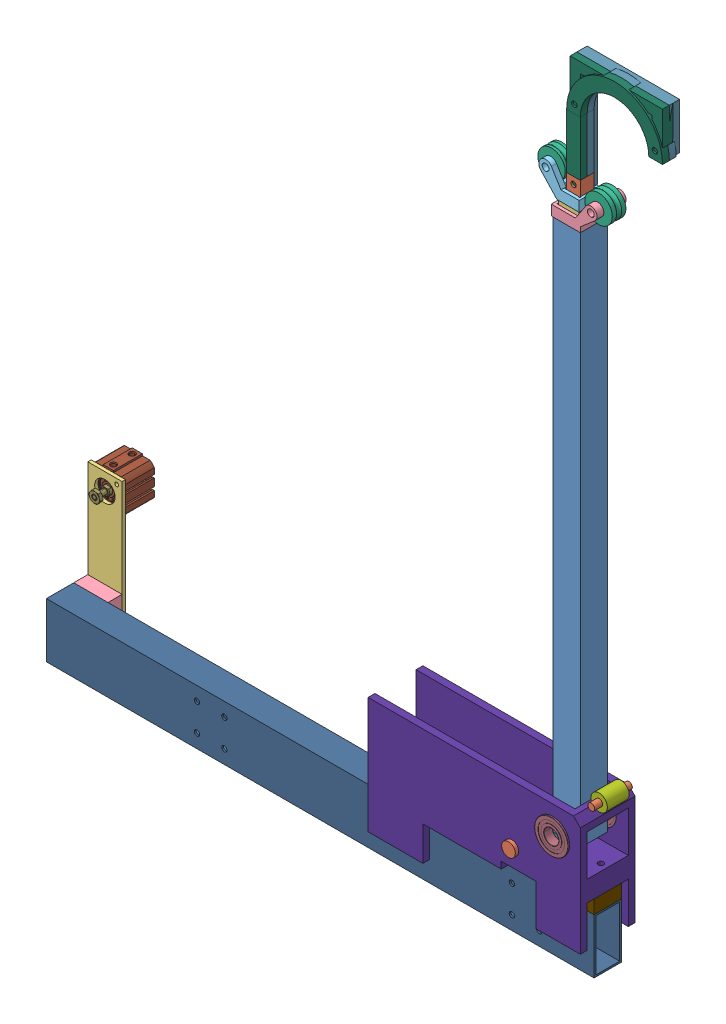
SolidWorks assembly Climber Assembly, configuration Default. Lengths in mm.
Overall size (565.24 723.26 84.45).
30 component instances, 22 part files, 39 mates.
Components (placement in the parent):
- Climber-1: Climber [Default] at (16.6995 73.025 101.2015) x (-1 0 0) z (0 0 -1) size (78.21 544.54 26.99) (flexible)
  - Tubes-1: Tubes [Default] at origin size (25.4 501.65 25.4)
  - Tubes3-1: Tubes3 [Default] at (0 21.59 0) size (12.7 508 12.7)
  - Tubes2-1: Tubes2 [Default] at (1.0954 19.05 0) size (19.05 495.3 19.05)
  - Cap-1: Cap [Default] at (0 504.19 0) x (-1 0 0) z (0 0 1) size (42.42 26.35 26.99)
  - Cap2-1: Cap2 [Default] at (1.0954 516.89 0) x (-1 0 0) z (0 0 1) size (37.5 26.99 20.64)
  - Roller-1: Roller [Default] at (21.9234 528.0025 -4.7942) x (0.375568 0.926795 0) z (0 0 1) size (25.4 25.4 9.59)
  - Roller-2: Roller [2nd Stage] at (-23.2093 515.3025 -6.3182) x (0.375568 0.926795 0) z (0 0 1) size (25.4 25.4 12.64)
  - Space-1: Space [Default] at (-27.5695 42.3738 -10.16) x (0.938392 0.345574 0) z (0 0 1) size (15.24 15.24 20.32)
  - Part1-1: Part1 [Default] at (2.2782 31.75 -0.9829) x (1 0 0) z (0 1 0) size (22.12 22.12 25.4)
  - Part2-1: Part2 [Default] at (0 34.29 0) x (0 0 1) z (0 1 0) size (15.96 15.78 25.4)
- Robot mount-1: Robot mount [Default] at (-465.9005 0 101.2015) x (0 0 -1) z (1 0 0) size (25.4 50.8 508)
- Pneumatic_Cylinder-1: Pneumatic_Cylinder [Default] at (-450.1144 100.2284 58.7835) size (31.75 33.34 39.89) (flexible)
  - Pneumatic_Cylinder_body-1: Pneumatic_Cylinder_body [Default] at origin size (31.75 33.34 26.92)
  - Pneumatic_Cylinder_pistion-1: Pneumatic_Cylinder_pistion [Default] x (0.356813 -0.934176 0) z (0 0 1) size (18.95 18.95 35.28)
- 0.5 in Bearing-1: 0.5 in Bearing [Default] at (16.6995 82.55 124.2202) x (0.99994 -0.010999 0) z (0 0 1) size (31.12 31.12 7.94)
- Hook 2-1: Hook 2 [Default] at (-15.7466 559.6581 -9.8676) size (88.9 107.95 12.7)
  - Hook Left-1: Hook Left [Default] at (32.4461 30.2569 104.7191) size (88.9 107.95 11.11)
  - Hook Right-1: Hook Right [Default] at (32.4461 30.2569 111.0691) size (88.9 107.95 11.11)
- Pin-1: Pin [Default] at (16.6995 136.525 85.9615) x (-0.380163 -0.92492 0) z (0 0 1) size (10.79 10.79 19.05)
- Hinge Mount-1: Hinge Mount [Default] at (16.6995 47.625 101.2015) x (0 0 1) z (-1 0 0) size (50.8 107.95 196.85)
- Foam-1: Foam [Default] at (-29.338 31.75 113.9015) size (71.44 12.7 25.4)
- 0.5 in Bearing-4: 0.5 in Bearing [Default] at (16.6995 82.55 78.1827) x (-0.923728 -0.383049 0) z (0 0 -1) size (31.12 31.12 7.94)
- Spring-body-1: Spring-body [Default] at (-21.4005 53.975 98.0265) x (-0.715331 -0.698786 0) z (0 0 1) size (26.37 26.37 19.05)
- Rod-1: Rod [Default] at (16.6995 82.55 72.6265) x (-0.463083 0.886315 0) z (0 0 1) size (12.7 12.7 57.15) (hidden)
- Rod-2: Rod [Default] at (-21.4005 53.975 72.6265) x (-0.920175 0.391507 0) z (0 0 1) size (12.7 12.7 57.15)
- Rod-3: Rod [Small] at (44.2691 115.3988 83.739) x (-0.997762 0.066863 0) z (0 0 1) size (6.35 6.35 34.92)
- Foam-2: Foam [Short] at (-103.9505 31.75 88.5015) x (-1 0 0) z (0 0 -1) size (50.8 12.7 25.4)
- mount for the piston mount thingie-1: mount for the piston mount thingie [Default] at (-465.9005 -31.3055 72.2455) size (31.75 141.41 3.17)
- spacer for the piston mount thingie-1: spacer for the piston mount thingie [Default] at (-465.9005 -25.4 75.4205) size (31.75 50.8 13.08)
Mates (geometry in assembly coordinates):
- Coincident39: coincident anti-aligned: plane of Climber-1/Tubes3-1 through (16.6995 602.615 101.2015) normal (0 1 0); plane of Hook 2-1/Hook Left-1 through (16.6995 602.615 94.8515) normal (0 -1 0)
- Concentric9: concentric aligned: cylinder of Pin-1 through (16.6995 136.525 105.0115) axis (0 0 -1) radius 3.937; cylinder of Climber-1/Tubes-1 through (16.6995 136.525 104.4574) axis (0 0 -1) radius 5.08
- LimitDistance1: limit distance = 0 mm anti-aligned: plane of Climber-1/Tubes-1 through (29.3995 574.675 88.5015) normal (0 0 -1); plane of Pin-1 through (16.6995 136.525 88.5015) normal (0 0 1)
- Parallel1: parallel anti-aligned: plane of Robot mount-1 through (42.0995 -25.4 88.5015) normal (0 0 -1); plane of Hinge Mount-1 through (-8.7005 0 82.1515) normal (0 0 1)
- Width2: width anti-aligned: plane of Hinge Mount-1 through (-8.7005 0 82.1515) normal (0 0 1); plane of Robot mount-1 through (-8.7005 38.1 120.2515) normal (0 0 -1); plane of Hinge Mount-1 through (42.0995 -25.4 88.5015) normal (0 0 -1); plane of Robot mount-1 through (42.0995 -25.4 113.9015) normal (0 0 1)
- Coincident41: coincident anti-aligned: plane of Robot mount-1 through (42.0995 25.4 113.9015) normal (0 1 0); plane of Foam-1 through (-29.338 25.4 113.9015) normal (0 -1 0)
- Coincident42: coincident aligned: plane of Robot mount-1 through (42.0995 -25.4 88.5015) normal (0 0 -1); plane of Foam-1 through (-29.338 38.1 88.5015) normal (0 0 -1)
- Coincident43: coincident anti-aligned: plane of Hinge Mount-1 through (-8.7005 38.1 82.1515) normal (0 -1 0); plane of Foam-1 through (-29.338 38.1 113.9015) normal (0 1 0)
- Coincident44: coincident aligned: plane of Hinge Mount-1 through (42.0995 47.625 101.2015) normal (1 0 0); plane of Foam-1 through (42.0995 38.1 113.9015) normal (1 0 0)
- Coincident45: coincident aligned: plane of Robot mount-1 through (42.0995 0 101.2015) normal (1 0 0); plane of Foam-1 through (42.0995 38.1 113.9015) normal (1 0 0)
- Concentric10: concentric aligned: cylinder of Hinge Mount-1 through (16.6995 82.55 126.6015) axis (0 0 -1) radius 14.2875; cylinder of 0.5 in Bearing-4 through (16.6995 82.55 24.9338) axis (0 0 -1) radius 14.2875
- Coincident46: coincident anti-aligned: plane of Hinge Mount-1 through (-8.7005 107.95 75.8015) normal (0 0 -1); plane of 0.5 in Bearing-4 through (11.2267 95.7478 75.8015) normal (0 0 1)
- Concentric11: concentric anti-aligned: cylinder of 0.5 in Bearing-1 through (16.6995 82.55 177.4691) axis (0 0 1) radius 14.2875; cylinder of Hinge Mount-1 through (16.6995 82.55 126.6015) axis (0 0 -1) radius 14.2875
- Coincident47: coincident anti-aligned: plane of 0.5 in Bearing-1 through (16.8567 96.8366 126.6015) normal (0 0 -1); plane of Hinge Mount-1 through (-8.7005 0 126.6015) normal (0 0 1)
- Concentric12: concentric aligned: cylinder of Climber-1/Tubes-1 through (16.6995 82.55 113.9015) axis (0 0 -1) radius 6.35; cylinder of 0.5 in Bearing-4 through (16.6995 82.55 24.9338) axis (0 0 -1) radius 6.875
- Width3: width anti-aligned: plane of Climber-1/Tubes-1 through (29.3995 574.675 113.9015) normal (0 0 1); plane of Hinge Mount-1 through (29.3995 574.675 88.5015) normal (0 0 -1); plane of Climber-1/Tubes-1 through (-8.7005 107.95 120.2515) normal (0 0 -1); plane of Hinge Mount-1 through (-8.7005 57.15 82.1515) normal (0 0 1)
- Coincident52: coincident anti-aligned: plane of Climber-1/Tubes3-1 through (21.462 602.615 107.5515) normal (-1 0 0); plane of Hook 2-1/Hook Right-1 through (21.462 589.915 101.2015) normal (1 0 0)
- Coincident53: coincident anti-aligned: plane of Climber-1/Tubes3-1 through (23.0495 602.615 96.439) normal (0 0 1); plane of Hook 2-1/Hook Left-1 through (11.937 589.915 96.439) normal (0 0 -1)
- LimitAngle1: limit planar angle = 1.570796 rad aligned: plane of Climber-1/Tubes-1 through (29.3995 574.675 113.9015) normal (1 0 0); plane of Robot mount-1 through (42.0995 25.4 113.9015) normal (0 1 0)
- Coincident54: coincident aligned: plane of Climber-1/Tubes-1 through (29.3995 574.675 88.5015) normal (0 0 -1); circle of Spring-body-1
- Concentric13: concentric aligned: circle of Hinge Mount-1; circle of Spring-body-1
- Concentric14: concentric aligned: cylinder of 0.5 in Bearing-4 through (16.6995 82.55 24.9338) axis (0 0 -1) radius 12.2875; cylinder of Rod-1 through (16.6995 82.55 129.7765) axis (0 0 -1) radius 6.35
- Width4: width aligned: plane of Rod-1 through (16.6995 82.55 129.7765) normal (0 0 1); plane of Hinge Mount-1 through (16.6995 82.55 72.6265) normal (0 0 -1); plane of Rod-1 through (-8.7005 0 126.6015) normal (0 0 1); plane of Hinge Mount-1 through (-8.7005 107.95 75.8015) normal (0 0 -1)
- Concentric15: concentric aligned: cylinder of Hinge Mount-1 through (-21.4005 53.975 126.6015) axis (0 0 -1) radius 6.35; cylinder of Rod-2 through (-21.4005 53.975 129.7765) axis (0 0 -1) radius 6.35
- Width5: width aligned: plane of Rod-2 through (-21.4005 53.975 72.6265) normal (0 0 -1); plane of Hinge Mount-1 through (-21.4005 53.975 129.7765) normal (0 0 1); plane of Rod-2 through (-8.7005 107.95 75.8015) normal (0 0 -1); plane of Hinge Mount-1 through (-8.7005 0 126.6015) normal (0 0 1)
- Concentric16: concentric anti-aligned: cylinder of Climber-1/Space-1 through (44.2691 115.3988 91.0415) axis (0 0 1) radius 7.62; cylinder of Rod-3 through (44.2691 115.3988 118.664) axis (0 0 -1) radius 3.175
- Width6: width anti-aligned: plane of Rod-3 through (44.2691 115.3988 118.664) normal (0 0 1); plane of Climber-1/Mount-1 through (44.2691 115.3988 83.739) normal (0 0 -1); plane of Rod-3 through (16.6795 119.8438 85.3265) normal (0 0 -1); plane of Climber-1/Mount-2 through (16.6795 119.8438 117.0765) normal (0 0 1)
- Coincident61: coincident anti-aligned: plane of Robot mount-1 through (42.0995 25.4 113.9015) normal (0 1 0); plane of Foam-2 through (-103.9505 25.4 88.5015) normal (0 -1 0)
- Coincident64: coincident aligned: plane of Robot mount-1 through (42.0995 -25.4 113.9015) normal (0 0 1); plane of Foam-2 through (-103.9505 38.1 113.9015) normal (0 0 1)
- Coincident65: coincident aligned: plane of Hinge Mount-1 through (-154.7505 47.625 101.2015) normal (-1 0 0); plane of Foam-2 through (-154.7505 38.1 88.5015) normal (-1 0 0)
- Coincident66: coincident anti-aligned: plane of Robot mount-1 through (42.0995 -25.4 88.5015) normal (0 0 -1); plane of spacer for the piston mount thingie-1 through (-465.9005 -25.4 88.5015) normal (0 0 1)
- Concentric17: concentric anti-aligned: circle of Robot mount-1; circle of spacer for the piston mount thingie-1
- Concentric18: concentric anti-aligned: circle of Robot mount-1; circle of spacer for the piston mount thingie-1
- Coincident69: coincident anti-aligned: plane of mount for the piston mount thingie-1 through (-465.9005 -31.3055 75.4205) normal (0 0 1); plane of spacer for the piston mount thingie-1 through (-465.9005 -25.4 75.4205) normal (0 0 -1)
- Concentric19: concentric aligned: circle of mount for the piston mount thingie-1; circle of spacer for the piston mount thingie-1
- Concentric20: concentric aligned: circle of mount for the piston mount thingie-1; circle of spacer for the piston mount thingie-1
- Coincident73: coincident anti-aligned: plane of Pneumatic_Cylinder-1/Pneumatic_Cylinder_body-1 through (-450.1144 100.2284 72.2455) normal (0 0 1); plane of mount for the piston mount thingie-1 through (-465.9005 -31.3055 72.2455) normal (0 0 -1)
- Concentric25: concentric aligned: cylinder of Pneumatic_Cylinder-1/Pneumatic_Cylinder_body-1 through (-461.0745 89.2683 72.2455) axis (0 0 1) radius 1.7526; cylinder of mount for the piston mount thingie-1 through (-461.0745 89.2683 72.2455) axis (0 0 1) radius 1.7526
- Concentric26: concentric aligned: cylinder of Pneumatic_Cylinder-1/Pneumatic_Cylinder_body-1 through (-439.1543 111.1885 72.2455) axis (0 0 1) radius 1.7526; cylinder of mount for the piston mount thingie-1 through (-439.1543 111.1885 72.2455) axis (0 0 1) radius 1.7526
